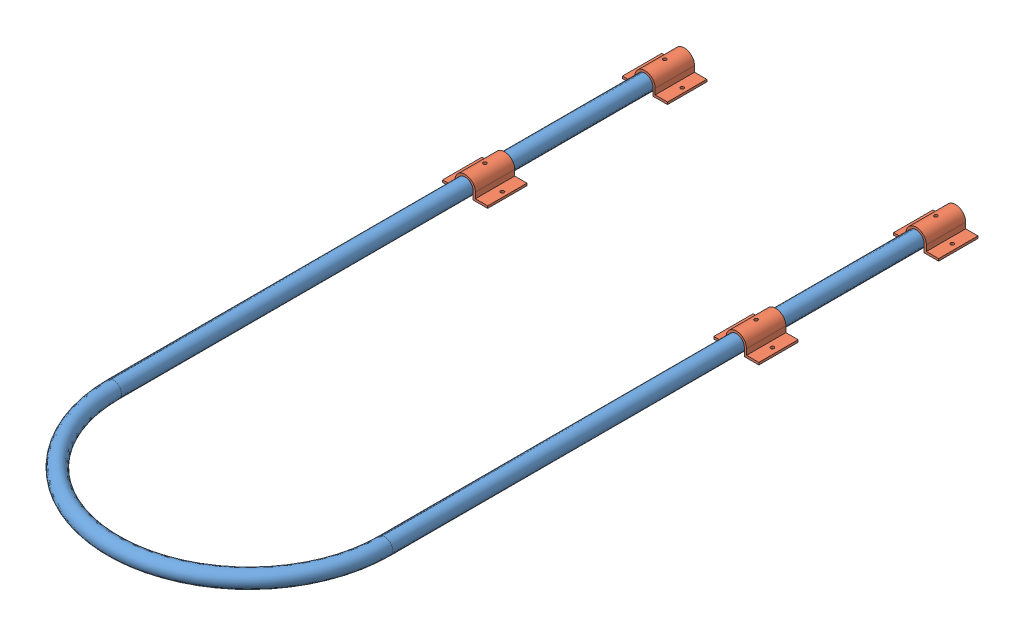
SolidWorks assembly Support Ring Assembly, configuration Default. Lengths in mm.
Overall size (562.74 32.45 1271.52).
5 component instances, 2 part files, 7 mates.
Components (placement in the parent):
- Round Bar-2: Round Bar [Default] at (0 0 478.0045) size (511.05 28.45 1271.52)
- circular bracket-2: circular bracket [Default] at (241.3 -10.224 -217.9672) size (80.14 32.45 70)
- circular bracket-3: circular bracket [Default] at (-241.3 -10.224 -147.9672) x (-1 0 0) z (0 0 -1) size (80.14 32.45 70)
- circular bracket-4: circular bracket [Default] at (241.3 -10.224 -537.9955) size (80.14 32.45 70)
- circular bracket-5: circular bracket [Default] at (-241.3 -10.224 -467.9955) x (-1 0 0) z (0 0 -1) size (80.14 32.45 70)
Mates (geometry in assembly coordinates):
- Coincident1: coordinate: point of Round Bar-2
- Concentric2: concentric: cylinder of Round Bar-2 through (241.3 0 190.2749) axis (0 0 -1) radius 14.224; cylinder of circular bracket-2 through (241.3 0 -217.9672) axis (0 0 -1) radius 14.224
- Parallel1: parallel anti-aligned: plane of circular bracket-2 through (255.524 -14.224 -147.9672) normal (0 -1 0)
- Concentric4: concentric: cylinder of Round Bar-2 through (241.3 0 190.2749) axis (0 0 -1) radius 14.224; cylinder of circular bracket-4 through (241.3 0 -537.9955) axis (0 0 -1) radius 14.224
- Parallel3: parallel anti-aligned: plane of circular bracket-4 through (255.524 -14.224 -467.9955) normal (0 -1 0)
- Concentric5: concentric: cylinder of Round Bar-2 through (-241.3 0 -825.7251) axis (0 0 1) radius 14.224; cylinder of circular bracket-3 through (-241.3 0 -147.9672) axis (0 0 1) radius 14.224
- Coincident2: coincident aligned: plane of Round Bar-2 through (241.3 0 -537.9955) normal (0 0 -1); plane of circular bracket-4 through (241.3 -10.224 -537.9955) normal (0 0 -1)
